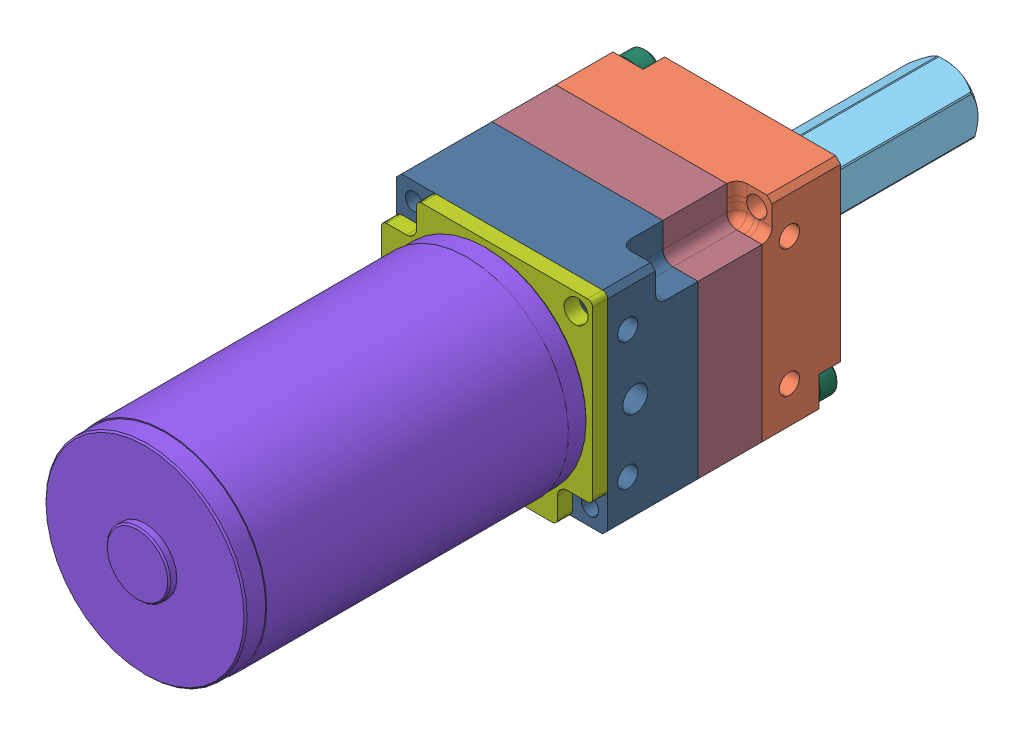
SolidWorks assembly VersaPlanetary-1-Stage-with-BAG-Motor, configuration Default. Lengths in mm.
Overall size (62.06 62.06 160.81).
22 component instances, 15 part files, 0 mates.
Components (placement in the parent):
- 217-2742-001 Rev4-1: 217-2742-001 Rev4 [Default] at (0 0 -19.9002) x (0 0 1) z (-1 0 0) size (7 28 28)
- 217-2742-001 Rev4-2: 217-2742-001 Rev4 [Default] at (0 0 -28.305) x (0 0 1) z (-0.819238 -0.573454 0) size (7 28 28)
- 217-2625-002 Rev1-1: 217-2625-002 Rev1 [Default] at (0 0 -6.2) x (-1 0 0) z (0 0 1) size (42 42 17.13)
- 217-2625-018 Rev1_98541A410-1: 217-2625-018 Rev1_98541A410 [Default] at (0 0 -12.4002) x (0 0 -1) z (0.980859 -0.194721 0) size (1 19.6 17.4)
- 217-2625-017 Rev1_9714K61-1: 217-2625-017 Rev1_9714K61 [Default] at (0 0 -20.9002) x (-0.695225 0.718792 0) z (-0.718792 -0.695225 0) size (28.51 4.98 30.18)
- Ouput Shafts^VersaPlanetary_500 Hex-1: Ouput Shafts^VersaPlanetary_500 Hex [Default] at (0 0 -20.5526) x (-0.995515 -0.094608 0) z (0 0 -1) size (17 17 64.12)
  - 217-2625-003 Rev1-1: 217-2625-003 Rev1 [Default] at origin size (17 17 64.12)
- 217-3564-000 Rev1_BAG-1: 217-3564-000 Rev1_BAG [Default] at (0 0 18) size (42 42 81.5)
  - 217-2625-011 Rev1-1: 217-2625-011 Rev1 [Default] at (0 0 -5.25) x (1 0 0) z (0 -1 0) size (8.01 7.5 7.94)
  - 217-2822-003 Rev4-1: 217-2822-003 Rev4 [Default] at (0 0 1.5) size (42 42 4.8)
  - 217-3351-1: 217-3351 [Default] at (0 0 3) x (0 1 0) z (0 0 -1) size (40.4 40.4 81.5)
- Input Housing^VersaPlanetary-1: Input Housing^VersaPlanetary [Default] at (-18.5 13.6657 1) x (0 0 -1) z (-0.885621 0.464408 0) size (20 56.7 56.7)
  - PINL-M020-006-S-1: PINL-M020-006-S [Default] at origin size (6 2 2)
  - 217-2625-001 Rev1-1: 217-2625-001 Rev1 [Default] at (-9.5 3.511 -22.7304) x (0 -0.464408 -0.885621) z (-1 0 0) size (42 42 18)
  - 217-2625-009 Rev1-1: 217-2625-009 Rev1 [Default] at (-6.02 3.511 -22.7304) x (0 0.885621 -0.464408) z (1 0 0) size (18 18 13)
  - SSS1032-0125ZB_94105A824-1: SSS1032-0125ZB_94105A824 [Default] at (-11.495 6.7192 -16.6126) x (-0.636804 0.682837 -0.35807) z (0 0.464408 0.885621) size (4.83 4.84 3.3)
- 217-2816 Rev1-1: 217-2816 Rev1 [Default] at (0 0 -6.35) x (1 0 0) z (0 0 -1) size (42 42 14.5)
  - 217-2816-001 Rev1-1: 217-2816-001 Rev1 [Default] at origin size (42 42 14.5)
- 217-2817 Rev1-1: 217-2817 Rev1 [Default] at (0 0 -10.8) x (-0.517538 0.85566 0) z (0 0 -1) size (21.94 21.95 12.7)
  - 217-2724-001 Rev1_Sun_Driver01-1: 217-2724-001 Rev1_Sun_Driver01 [Default] at (0 0 -6.375) x (0.984808 0.173648 0) z (0 0 1) size (18.94 18.95 12.7)
- SSA_SSA0832-1250ZC-1: SSA_SSA0832-1250ZC [Default] at (-17.5 17.5 -24.061) x (0.699203 0.714923 0) z (-0.714923 0.699203 0) size (6.73 35.81 6.73)
- SSA_SSA0832-1250ZC-2: SSA_SSA0832-1250ZC [Default] at (17.5 -17.5 -24.061) x (-0.999999 0.001665 0) z (-0.001665 -0.999999 0) size (6.73 35.81 6.73)
